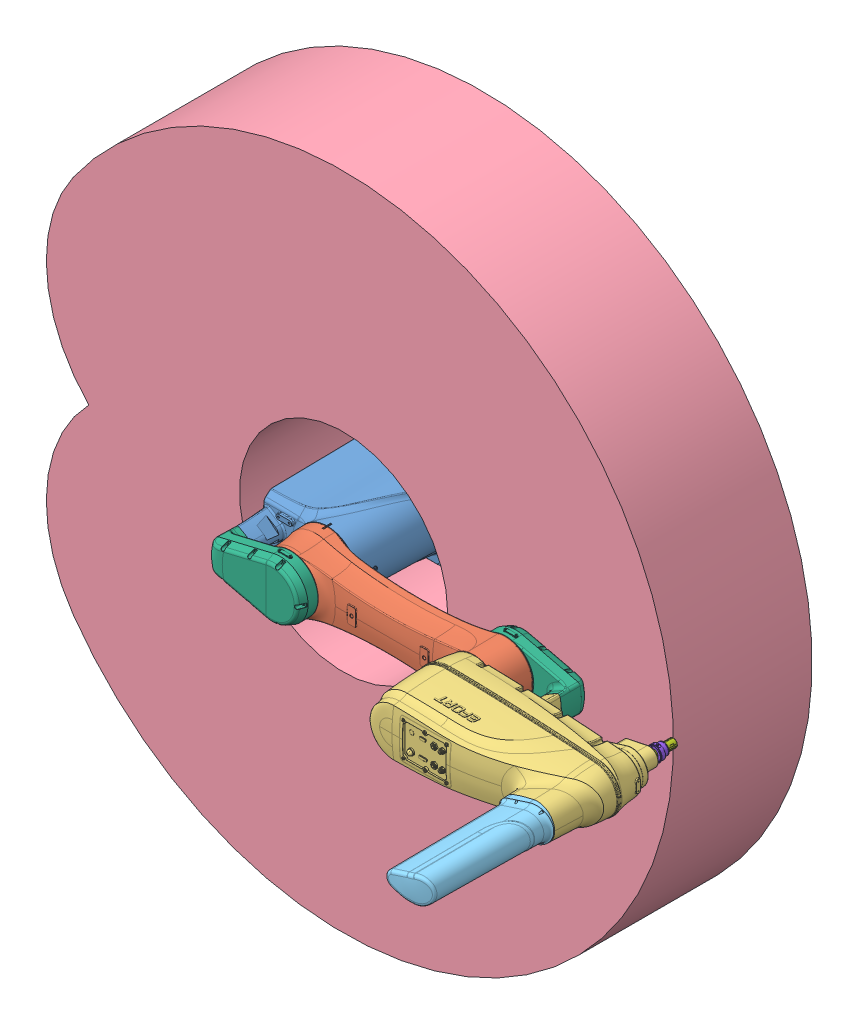
SolidWorks assembly ESR20-1000Z42 机器人数模-2016 V1.1, configuration 默认. Lengths in mm.
Overall size (1972.53 2000 1207.21).
10 component instances, 8 part files, 26 mates.
Components (placement in the parent):
- 复件 底座部分^ESR20-1000Z42 机器人数模-2016 V1.1-1: 复件 底座部分^ESR20-1000Z42 机器人数模-2016 V1.1 [默认] at (0 0 22) x (-1 0 0) z (0 1 0) size (400.93 380.86 258.3) (virtual)
- 复件 大臂^ESR20-1000Z42 机器人数模-2016 V1.1-1: 复件 大臂^ESR20-1000Z42 机器人数模-2016 V1.1 [默认] at (550 0 408) x (0 -1 0) z (0 0 1) size (185.28 726.71 110.46) (virtual)
- 复件 小臂部分^ESR20-1000Z42 机器人数模-2016 V1.1-1: 复件 小臂部分^ESR20-1000Z42 机器人数模-2016 V1.1 [默认] at (550 0 486) x (-1 0 0) z (0 0 1) size (613.99 190.73 342.72) (virtual)
- 复件 运动范围^ESR20-1000Z42 机器人数模-2016 V1.1-1: 复件 运动范围^ESR20-1000Z42 机器人数模-2016 V1.1 [默认] at (0 0 248.1) size (1900.53 2000 420) (virtual)
- 复件 丝杆外壳^ESR20-1000Z42 机器人数模-2016 V1.1-1: 复件 丝杆外壳^ESR20-1000Z42 机器人数模-2016 V1.1 [默认] at (550 0 486) x (-1 0 0) z (0 0 1) size (154.56 108.36 375.44) (virtual)
- 复件 线缆臂部分^ESR20-1000Z42 机器人数模-2016 V1.1-1: 复件 线缆臂部分^ESR20-1000Z42 机器人数模-2016 V1.1 [默认] at (0 0 410) x (0 1 0) z (0 0 1) size (172 283.64 85.47) (virtual)
- 复件 丝杆^ESR20-1000Z42 机器人数模-2016 V1.1-1: 复件 丝杆^ESR20-1000Z42 机器人数模-2016 V1.1 [默认] at (1000 0 648.1) x (-0.923728 -0.383049 0) z (0 0 -1) size (27.83 26.14 742.73) (virtual)
- 复件 辅助杆^ESR20-1000Z42 机器人数模-2016 V1.1-1: 复件 辅助杆^ESR20-1000Z42 机器人数模-2016 V1.1 [默认] at (1000 0 648.1) x (-0.383049 0.923728 0) z (0 0 -1) size (44.99 43 29.4) (virtual)
- 复件 线缆臂部分^ESR20-1000Z42 机器人数模-2016 V1.1-2: 复件 线缆臂部分^ESR20-1000Z42 机器人数模-2016 V1.1 [默认] at (550 0 306) x (0 1 0) z (0 0 -1) size (172 283.64 85.47) (virtual)
- 复件 辅助杆^ESR20-1000Z42 机器人数模-2016 V1.1-2: 复件 辅助杆^ESR20-1000Z42 机器人数模-2016 V1.1 [默认] at (1000 0 613.1) x (-0.383049 0.923728 0) z (0 0 1) size (44.99 43 29.4) (virtual)
Mates (geometry in assembly coordinates):
- 重合1: coordinate: point of 复件 底座部分^ESR20-1000Z42 机器人数模-2016 V1.1-1; point of assembly
- 同心1: concentric anti-aligned: cone of 复件 底座部分^ESR20-1000Z42 机器人数模-2016 V1.1-1 through (0 0 297) axis (0 0 1); cylinder of 复件 大臂^ESR20-1000Z42 机器人数模-2016 V1.1-1 through (0 0 300) axis (0 0 -1) radius 92.501
- 距离1: distance = 1 mm anti-aligned: plane of 复件 大臂^ESR20-1000Z42 机器人数模-2016 V1.1-1 through (92.501 0 298) normal (0 0 -1); plane of 复件 底座部分^ESR20-1000Z42 机器人数模-2016 V1.1-1 through (0 0 297) normal (0 0 1)
- 同心2: concentric aligned: cylinder of 复件 大臂^ESR20-1000Z42 机器人数模-2016 V1.1-1 through (550 0 172.4685) axis (0 0 1) radius 78.5; cylinder of 复件 小臂部分^ESR20-1000Z42 机器人数模-2016 V1.1-1 through (550 0 402) axis (0 0 1) radius 82.5
- 距离2: distance = 1 mm anti-aligned: plane of 复件 小臂部分^ESR20-1000Z42 机器人数模-2016 V1.1-1 through (550 0 404) normal (0 0 -1); plane of 复件 大臂^ESR20-1000Z42 机器人数模-2016 V1.1-1 through (550 0 403) normal (0 0 1)
- 同心3: concentric aligned: cone of 复件 大臂^ESR20-1000Z42 机器人数模-2016 V1.1-1 through (0 0 298) axis (0 0 1); cylinder of 复件 线缆臂部分^ESR20-1000Z42 机器人数模-2016 V1.1-1 through (0 0 409) axis (0 0 1) radius 84
- 重合4: coincident anti-aligned: plane of 复件 底座部分^ESR20-1000Z42 机器人数模-2016 V1.1-1 through (-167.8984 30.6112 380.5) normal (0 0 1); plane of 复件 线缆臂部分^ESR20-1000Z42 机器人数模-2016 V1.1-1 through (-292.6828 0 380.5) normal (0 0 -1)
- 重合5: coincident aligned: plane of 复件 底座部分^ESR20-1000Z42 机器人数模-2016 V1.1-1 through (0 0 22) normal (0 1 0); plane of 复件 线缆臂部分^ESR20-1000Z42 机器人数模-2016 V1.1-1
- 同心4: concentric aligned: cylinder of 复件 大臂^ESR20-1000Z42 机器人数模-2016 V1.1-1 through (550 0 310) axis (0 0 -1) radius 84.1584; cylinder of 复件 线缆臂部分^ESR20-1000Z42 机器人数模-2016 V1.1-2 through (550 0 307) axis (0 0 -1) radius 84
- 重合6: coincident anti-aligned: plane of 复件 小臂部分^ESR20-1000Z42 机器人数模-2016 V1.1-1 through (698.7822 18.3773 335.5) normal (0 0 -1); plane of 复件 线缆臂部分^ESR20-1000Z42 机器人数模-2016 V1.1-2 through (842.6828 0 335.5) normal (0 0 1)
- 重合7: coincident anti-aligned: plane of 复件 小臂部分^ESR20-1000Z42 机器人数模-2016 V1.1-1; plane of 复件 线缆臂部分^ESR20-1000Z42 机器人数模-2016 V1.1-2
- 同心5: concentric aligned: cylinder of 复件 丝杆^ESR20-1000Z42 机器人数模-2016 V1.1-1 through (1000 0 648.1) axis (0 0 -1) radius 12.5; cylinder of 复件 辅助杆^ESR20-1000Z42 机器人数模-2016 V1.1-1 through (1000 0 278.1) axis (0 0 -1) radius 12.5
- 同心6: concentric anti-aligned: cylinder of 复件 丝杆^ESR20-1000Z42 机器人数模-2016 V1.1-1 through (1000 0 300.6) axis (-0.383049 0.923728 0) radius 1.65; cylinder of 复件 辅助杆^ESR20-1000Z42 机器人数模-2016 V1.1-1 through (1009.0017 -21.7076 300.6) axis (0.383049 -0.923728 0) radius 3.5
- 同心7: concentric anti-aligned: cylinder of 复件 丝杆^ESR20-1000Z42 机器人数模-2016 V1.1-1 through (1000 0 648.1) axis (0 0 -1) radius 12.5; cylinder of 复件 辅助杆^ESR20-1000Z42 机器人数模-2016 V1.1-2 through (1000 0 983.1) axis (0 0 1) radius 12.5
- 重合8: coincident aligned: plane of 复件 丝杆^ESR20-1000Z42 机器人数模-2016 V1.1-1 through (877.5909 -77.8245 983.1) normal (0 0 1); plane of 复件 辅助杆^ESR20-1000Z42 机器人数模-2016 V1.1-2 through (993.2966 16.1652 983.1) normal (0 0 1)
- 重合9: coincident aligned: plane of 复件 辅助杆^ESR20-1000Z42 机器人数模-2016 V1.1-1 through (1007.4695 -18.0127 278.1) normal (0.383049 -0.923728 0); plane of 复件 辅助杆^ESR20-1000Z42 机器人数模-2016 V1.1-2 through (1007.4695 -18.0127 983.1) normal (0.383049 -0.923728 0)
- 同心8: concentric aligned: cylinder of 复件 小臂部分^ESR20-1000Z42 机器人数模-2016 V1.1-1 through (1000 0 -160.4372) axis (0 0 -1) radius 21; cylinder of 复件 丝杆^ESR20-1000Z42 机器人数模-2016 V1.1-1 through (1000 0 648.1) axis (0 0 -1) radius 12.5
- 同心9: concentric anti-aligned: cylinder of 复件 小臂部分^ESR20-1000Z42 机器人数模-2016 V1.1-1 through (906 0 667.2208) axis (0 0 1) radius 1.25; cone of 复件 丝杆外壳^ESR20-1000Z42 机器人数模-2016 V1.1-1 through (906 0 663.2208) axis (0 0 -1)
- 重合10: coincident anti-aligned: plane of 复件 小臂部分^ESR20-1000Z42 机器人数模-2016 V1.1-1 through (975.5375 0 660.2208) normal (0 0 1); plane of 复件 丝杆外壳^ESR20-1000Z42 机器人数模-2016 V1.1-1 through (550 0 660.2208) normal (0 0 -1)
- 同心10: concentric anti-aligned: cylinder of 复件 小臂部分^ESR20-1000Z42 机器人数模-2016 V1.1-1 through (1024 41.5692 667.2208) axis (0 0 1) radius 1.25; cone of 复件 丝杆外壳^ESR20-1000Z42 机器人数模-2016 V1.1-1 through (1024 41.5692 663.2208) axis (0 0 -1)
- 同心11: concentric aligned: cone of 复件 底座部分^ESR20-1000Z42 机器人数模-2016 V1.1-1 through (0 0 297) axis (0 0 1); cylinder of 复件 运动范围^ESR20-1000Z42 机器人数模-2016 V1.1-1 through (0 0 -171.9) axis (0 0 1) radius 315.4675
- 重合11: coincident aligned: plane of 复件 底座部分^ESR20-1000Z42 机器人数模-2016 V1.1-1 through (0 0 22) normal (0 1 0); plane of 复件 运动范围^ESR20-1000Z42 机器人数模-2016 V1.1-1 through (0 0 248.1) normal (0 1 0)
- 距离3: distance = 171.9 mm aligned: plane of 复件 底座部分^ESR20-1000Z42 机器人数模-2016 V1.1-1 through (0 0 0) normal (0 0 -1); plane of 复件 运动范围^ESR20-1000Z42 机器人数模-2016 V1.1-1 through (0 0 -171.9) normal (0 0 -1)
- LimitDistance1: limit distance = 10 mm anti-aligned: plane of 复件 辅助杆^ESR20-1000Z42 机器人数模-2016 V1.1-1 through (1000 0 307.5) normal (0 0 1); plane of 复件 小臂部分^ESR20-1000Z42 机器人数模-2016 V1.1-1 through (1020.9915 -0.5985 317.5) normal (0 0 -1)
- LimitAngle1: limit planar angle = 0 rad aligned: plane of 复件 底座部分^ESR20-1000Z42 机器人数模-2016 V1.1-1 through (-2.5 109.2 299.5) normal (1 0 0); plane of 复件 大臂^ESR20-1000Z42 机器人数模-2016 V1.1-1 through (-2.5 100 310.5) normal (1 0 0)
- LimitAngle2: limit planar angle = 0 rad aligned: plane of 复件 大臂^ESR20-1000Z42 机器人数模-2016 V1.1-1 through (459.5 -2.5 408) normal (0 1 0); plane of 复件 小臂部分^ESR20-1000Z42 机器人数模-2016 V1.1-1 through (460 -2.5 381.9453) normal (0 1 0)
